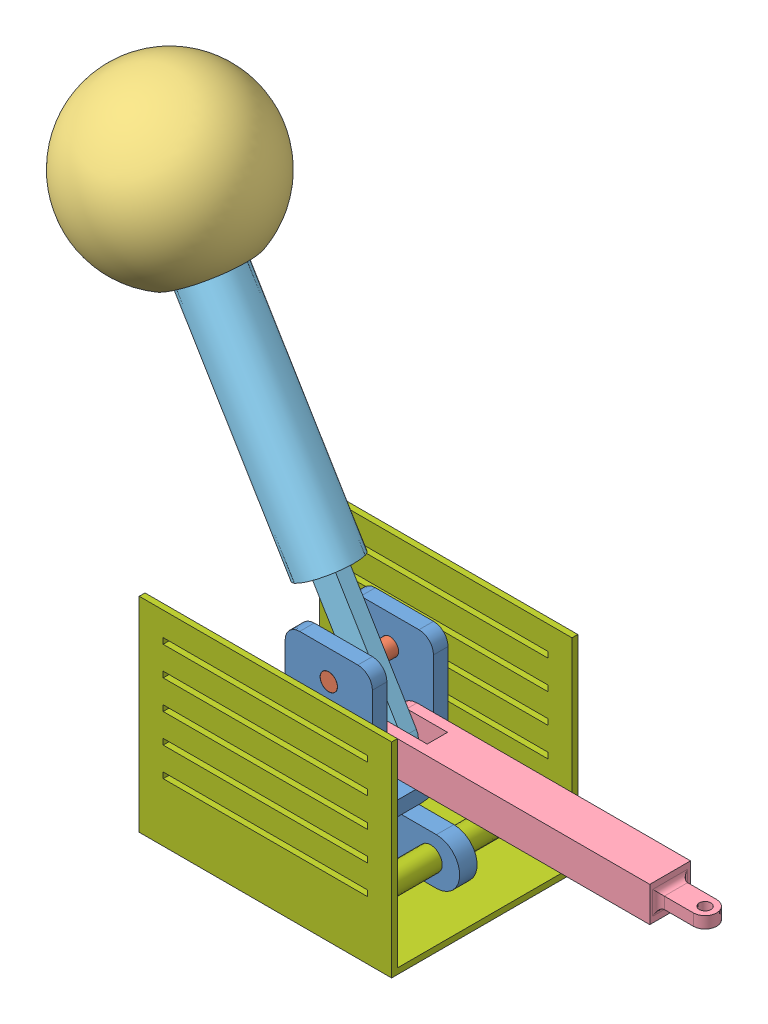
SolidWorks assembly Assembly, configuration Default. Lengths in mm.
Overall size (235.32 215.47 74.45).
7 component instances, 7 part files, 15 mates.
Components (placement in the parent):
- Box_Pivot-1: Box_Pivot [Default] at (11.9261 53.6915 54.2812) size (70 63 26)
- Big Post-1: Big Post [Default] at (11.9261 68.2515 41.2812) x (0.772904 -0.634523 0) z (0 0 1) size (5.9 5.9 26)
- Handle-1: Handle [Default] at (-55.7006 180.4461 54.2812) x (-0.240713 -0.145093 -0.95969) z (0.821924 0.495426 -0.28106) size (60 56 60)
- Link-1: Link [Default] at (116.2508 51.1226 54.2812) size (116 12 14)
- Post Handle-1: Post Handle [Default] at (-21.6291 123.9206 54.2812) x (-0.516235 0.856447 0) z (0 0 1) size (140 20 20)
- Small Post-1: Small Post [Default] at (22.2508 51.1226 47.2812) x (0.979703 -0.200456 0) z (0 0 1) size (5.9 5.9 14)
- Cover-1: Cover [Default] at (11.9261 53.6915 54.2812) size (86.74 70.25 64)
Mates (geometry in assembly coordinates):
- Concentric1: concentric anti-aligned: cylinder of Box_Pivot-1 through (11.9261 68.2515 41.2812) axis (0 0 1) radius 3; cylinder of Big Post-1 through (11.9261 68.2515 67.2812) axis (0 0 -1) radius 2.95
- Coincident1: coincident aligned: plane of Box_Pivot-1 through (26.9261 78.2515 67.2812) normal (0 0 1); plane of Big Post-1 through (11.9261 68.2515 67.2812) normal (0 0 1)
- Concentric2: concentric aligned: cylinder of Big Post-1 through (11.9261 68.2515 67.2812) axis (0 0 -1) radius 2.95; cylinder of Post Handle-1 through (11.9261 68.2515 56.7812) axis (0 0 -1) radius 3
- Width1: width anti-aligned: plane of Box_Pivot-1 through (26.9261 40.2515 46.2812) normal (0 0 1); plane of Box_Pivot-1 through (26.9261 78.2515 62.2812) normal (0 0 -1); plane of Post Handle-1 through (22.2508 51.1226 51.7812) normal (0 0 -1); plane of Post Handle-1 through (22.2508 51.1226 56.7812) normal (0 0 1)
- Concentric3: concentric aligned: cylinder of Handle-1 through (-48.4733 168.4558 54.2812) axis (0.516235 -0.856447 0) radius 6; cylinder of Post Handle-1 through (-47.4409 166.7429 54.2812) axis (0.516235 -0.856447 0) radius 6
- Coincident3: coincident anti-aligned: plane of Handle-1 through (-42.2785 158.1785 54.2812) normal (0.516235 -0.856447 0); plane of Post Handle-1 through (-42.2785 158.1785 54.2812) normal (-0.516235 0.856447 0)
- Concentric4: concentric aligned: cylinder of Link-1 through (22.2508 51.1226 61.2812) axis (0 0 -1) radius 3; cylinder of Post Handle-1 through (22.2508 51.1226 56.7812) axis (0 0 -1) radius 3
- Width2: width anti-aligned: plane of Link-1 through (16.2508 45.1226 50.7812) normal (0 0 1); plane of Link-1 through (36.2508 45.1226 57.7812) normal (0 0 -1); plane of Post Handle-1 through (22.2508 51.1226 51.7812) normal (0 0 -1); plane of Post Handle-1 through (22.2508 51.1226 56.7812) normal (0 0 1)
- Concentric5: concentric aligned: cylinder of Post Handle-1 through (22.2508 51.1226 56.7812) axis (0 0 -1) radius 3; cylinder of Small Post-1 through (22.2508 51.1226 61.2812) axis (0 0 -1) radius 2.95
- Width3: width anti-aligned: plane of Small Post-1 through (22.2508 51.1226 61.2812) normal (0 0 1); plane of Small Post-1 through (22.2508 51.1226 47.2812) normal (0 0 -1); plane of Link-1 through (22.2508 51.1226 47.2812) normal (0 0 -1); plane of Link-1 through (22.2508 51.1226 61.2812) normal (0 0 1)
- Parallel1: parallel aligned: plane of Box_Pivot-1 through (26.9261 36.2515 58.2812) normal (0 1 0); plane of Link-1 through (116.2508 57.1226 61.2812) normal (0 1 0)
- InPlace1: in place: plane of ? through (11.9261 53.6915 54.2812) normal (0 0 1); plane of ? through (11.9261 53.6915 54.2812) normal (0 0 1); moOrthogonalPlaneRef_w of ? through (11.9261 53.6915 54.2812) normal (0 0 1); plane of ? through (11.9261 53.6915 54.2812) normal (0 1 0); plane of ? through (11.9261 53.6915 54.2812) normal (0 0 1); plane of ? through (11.9261 53.6915 54.2812) normal (1 0 0); plane of ? through (11.9261 53.6915 54.2812) normal (0 0 1); unknown of ?
- Coincident4: coincident aligned: plane of Box_Pivot-1; plane of Cover-1
- Coincident5: coincident aligned: plane of Box_Pivot-1; plane of Cover-1 through (11.9261 53.6915 54.2812) normal (0 1 0)
- Coincident6: coincident anti-aligned: plane of Box_Pivot-1; plane of Cover-1 through (11.9261 53.6915 54.2812) normal (1 0 0)
